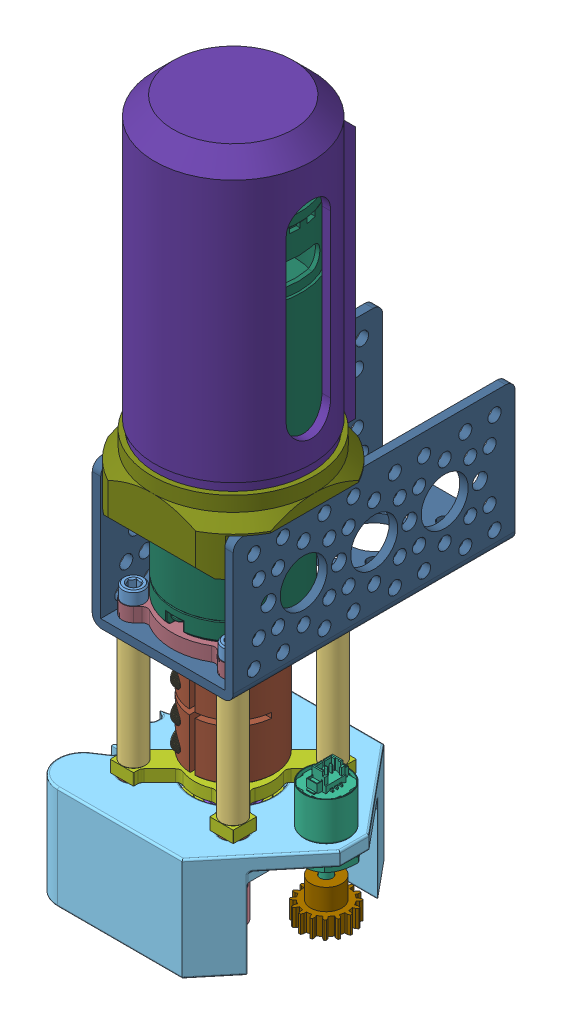
SolidWorks assembly Corner Steering Assembly, configuration Clockwise. Lengths in mm.
Overall size (61.41 192.93 84.4).
42 component instances, 17 part files, 59 mates.
Components (placement in the parent):
- 6-32_SHCS-1: 6-32_SHCS [6-32 SHCS X .250] at (32.5204 -0.254 70.6204) x (-0.999576 0 -0.029101) z (0 1 0)
- 6-32_SHCS-2: 6-32_SHCS [6-32 SHCS X .250] at (5.5796 -0.254 70.6204) x (0.563764 0 -0.825936) z (0 1 0)
- 6-32_SHCS-3: 6-32_SHCS [6-32 SHCS X .250] at (5.5796 -0.254 43.6796) x (-0.984166 0 -0.177249) z (0 1 0)
- 6-32_SHCS-4: 6-32_SHCS [6-32 SHCS X .250] at (32.5204 -0.254 43.6796) x (-0.906181 0 -0.422891) z (0 1 0)
- 6-32_L0_25 Spacer-1: 6-32_L0_25 Spacer [Default] at (5.5796 -34.925 43.6796) x (0 -1 0) z (-0.967859 0 0.251494)
- 6-32_L0_25 Spacer-2: 6-32_L0_25 Spacer [Default] at (32.5204 -34.925 43.6796) x (0 -1 0) z (-0.631957 0 0.775004)
- 6-32_L0_25 Spacer-3: 6-32_L0_25 Spacer [Default] at (5.5796 -34.925 70.6204) x (0 -1 0) z (0 0 1)
- 6-32_L0_25 Spacer-4: 6-32_L0_25 Spacer [Default] at (32.5204 -34.925 70.6204) x (0 -1 0) z (0 0 1)
- 6-32_SHCS-9: 6-32_SHCS [6-32 SHCS X .750] at (32.5204 -25.4 70.6204) x (1 0 0) z (0 -1 0)
- 6-32_SHCS-10: 6-32_SHCS [6-32 SHCS X .750] at (5.5796 -25.4 43.6796) x (1 0 0) z (0 -1 0)
- 6-32_SHCS-11: 6-32_SHCS [6-32 SHCS X .750] at (5.5796 -25.4 70.6204) x (1 0 0) z (0 -1 0)
- 6-32_SHCS-12: 6-32_SHCS [6-32 SHCS X .750] at (32.5204 -25.4 43.6796) x (1 0 0) z (0 -1 0)
- 1_25 threaded standoff-1: 1_25 threaded standoff [Default] at (32.5204 -31.75 43.6796) size (6.34 31.97 6.34)
- 1_25 threaded standoff-2: 1_25 threaded standoff [Default] at (32.5204 -31.75 70.6204) size (6.34 31.97 6.34)
- 1_25 threaded standoff-3: 1_25 threaded standoff [Default] at (5.5796 -31.75 43.6796) size (6.34 31.97 6.34)
- 1_25 threaded standoff-4: 1_25 threaded standoff [Default] at (5.5796 -31.75 70.6204) size (6.34 31.97 6.34)
- .25 D Shaft-1: .25 D Shaft [Default] at (19.05 -24.7728 57.15) x (-0.24409 0 -0.969753) z (-0.969753 0 0.24409)
- Encoder mount-1: Encoder mount [Default] at (19.05 -41.275 57.15)
- Absolute Encoder-1: Absolute Encoder [BEARING VERSION] at (44.196 -41.4528 57.15) x (0 -1 0) z (0 0 -1)
- 0.25 Pillow Bearing Block-1: 0.25 Pillow Bearing Block [Default] at (-9.6584 -13.2725 55.4365) x (0 0 1) z (1 0 0) size (33.27 5.08 33.27)
  - 0.25 Beaing Block-1: 0.25 Beaing Block [Default] at (1.7135 18.4775 28.7084) size (33.27 5.08 33.27)
  - 0.25 Bearing-1: 0.25 Bearing [Default] at (1.7135 21.1636 28.7084) x (0.837169 0 0.546944) z (0.546944 0 -0.837169) size (12.7 4.76 12.7)
- 0.25 Pillow Bearing Block-2: 0.25 Pillow Bearing Block [Default] at (20.7635 -62.9275 85.8584) x (-1 0 0) z (0 0 -1) size (33.27 5.08 33.27)
  - 0.25 Beaing Block-1: 0.25 Beaing Block [Default] at (1.7135 18.4775 28.7084) size (33.27 5.08 33.27)
  - 0.25 Bearing-1: 0.25 Bearing [Default] at (1.7135 21.1636 28.7084) x (0.837169 0 0.546944) z (0.546944 0 -0.837169) size (12.7 4.76 12.7)
- 0.125in Bore 32 Pitch Shaft Mount Pinion Gear-1: 0.125in Bore 32 Pitch Shaft Mount Pinion Gear [Default] at (44.196 -56.7055 57.15) x (-0.355189 0 -0.934794) z (0.934794 0 -0.355189)
- 3 Aluminum Channel-2: 3 Aluminum Channel [Default] at origin
- 0.25 to 6mm Clamping Coupler-1: 0.25 to 6mm Clamping Coupler [Default] at (55.1407 -34.8285 56.8026) x (1 0 0) z (0 1 0) size (50 22.2 75.17)
  - 625100-1: 625100 [Default] at (-36.0907 -0.3474 4.9835) size (22.23 22.2 28.58)
  - 632112_90128A121-1: 632112_90128A121 [Default] at (-1.3244 -7.8756 30.0025) x (0 0 -1) z (1 0 0) size (5.6 5.6 14.62)
  - 632112_90128A121-2: 632112_90128A121 [Default] at (-1.3244 -7.8756 23.5255) x (0 0 -1) z (1 0 0) size (5.6 5.6 14.62)
  - 632112_90128A121-3: 632112_90128A121 [Default] at (-1.3244 -7.8756 15.0165) x (0 0 -1) z (1 0 0) size (5.6 5.6 14.62)
  - 632112_90128A121-4: 632112_90128A121 [Default] at (-1.3244 -7.8756 8.5395) x (0 0 -1) z (1 0 0) size (5.6 5.6 14.62)
- motor mount-1: motor mount [Default] at (-39.8175 39.3823 49.9948) x (-1 0 0) z (0 0 1) size (33.02 8.74 33.02)
  - 555174-1: 555174 [Default] at (-58.8675 33.2863 7.1552) size (33.02 4.05 33.02)
  - 555174 screw_92005A116-1: 555174 screw_92005A116 [Default] at (-68.0596 28.5563 -2.0369) x (1 0 0) z (0 1 0) size (6 6 8.48)
  - 555174 screw_92005A116-2: 555174 screw_92005A116 [Default] at (-68.0596 28.5563 16.3474) x (0 0 -1) z (0 1 0) size (6 6 8.48)
  - 555174 screw_92005A116-3: 555174 screw_92005A116 [Default] at (-49.6753 28.5563 16.3474) x (-1 0 0) z (0 1 0) size (6 6 8.48)
  - 555174 screw_92005A116-4: 555174 screw_92005A116 [Default] at (-49.6753 28.5563 -2.0369) x (0 0 1) z (0 1 0) size (6 6 8.48)
- 638270_Planetary-Motor-1: 638270_Planetary-Motor [Default] at (19.05 6.096 57.15) x (1 0 0) z (0 -1 0) size (37 36.95 124.32)
- motor_mount_base_v2-1: motor_mount_base_v2 [Default] at (19.05 38.1 57.15) x (1 0 0) z (0 1 0) size (44 44 17.61)
- motor_mount_cap_v2-1: motor_mount_cap_v2 [Default] at (19.05 40.7106 57.15) x (1 0 0) z (0 1 0) size (42.38 46.99 83)
Mates (geometry in assembly coordinates):
- Concentric22: concentric anti-aligned: cylinder of Encoder mount-1 through (5.5796 -34.925 43.6796) axis (0 -1 0) radius 3.2258; cylinder of 6-32_L0_25 Spacer-1 through (5.5796 -41.275 43.6796) axis (0 1 0) radius 3.175
- Concentric23: concentric anti-aligned: cylinder of Encoder mount-1 through (32.5204 -34.925 43.6796) axis (0 -1 0) radius 3.2258; cylinder of 6-32_L0_25 Spacer-2 through (32.5204 -41.275 43.6796) axis (0 1 0) radius 3.175
- Concentric24: concentric anti-aligned: cylinder of Encoder mount-1 through (5.5796 -34.925 70.6204) axis (0 -1 0) radius 3.2258; cylinder of 6-32_L0_25 Spacer-3 through (5.5796 -41.275 70.6204) axis (0 1 0) radius 3.175
- Concentric25: concentric anti-aligned: cylinder of Encoder mount-1 through (32.5204 -34.925 70.6204) axis (0 -1 0) radius 3.2258; cylinder of 6-32_L0_25 Spacer-4 through (32.5204 -41.275 70.6204) axis (0 1 0) radius 3.175
- Coincident19: coincident aligned: plane of Encoder mount-1 through (19.05 -41.275 57.15) normal (0 -1 0); plane of 6-32_L0_25 Spacer-3 through (5.5796 -41.275 70.6204) normal (0 -1 0)
- Coincident20: coincident aligned: plane of Encoder mount-1 through (19.05 -41.275 57.15) normal (0 -1 0); plane of 6-32_L0_25 Spacer-1 through (5.5796 -41.275 43.6796) normal (0 -1 0)
- Coincident21: coincident aligned: plane of Encoder mount-1 through (19.05 -41.275 57.15) normal (0 -1 0); plane of 6-32_L0_25 Spacer-2 through (32.5204 -41.275 43.6796) normal (0 -1 0)
- Coincident22: coincident aligned: plane of Encoder mount-1 through (19.05 -41.275 57.15) normal (0 -1 0); plane of 6-32_L0_25 Spacer-4 through (32.5204 -41.275 70.6204) normal (0 -1 0)
- Concentric27: concentric aligned: cylinder of Encoder mount-1 through (44.196 -34.925 57.15) axis (0 -1 0) radius 5.08; cylinder of Absolute Encoder-1 through (44.196 -41.4528 57.15) axis (0 -1 0) radius 6.096
- Coincident24: coincident anti-aligned: plane of Encoder mount-1 through (19.05 -34.925 57.15) normal (0 1 0); plane of Absolute Encoder-1 through (39.7764 -34.925 57.15) normal (0 -1 0)
- Concentric28: concentric anti-aligned: cylinder of 0.25 Pillow Bearing Block-2/0.25 Bearing-1 through (19.05 -44.1452 57.15) axis (0 1 0) radius 3.175; cylinder of 0.25 Pillow Bearing Block-1/0.25 Bearing-1 through (19.05 -32.0548 57.15) axis (0 -1 0) radius 3.175
- Concentric29: concentric aligned: cylinder of 0.25 Pillow Bearing Block-2/0.25 Bearing-1 through (19.05 -44.1452 57.15) axis (0 1 0) radius 3.175; cylinder of .25 D Shaft-1 through (19.05 -88.2728 57.15) axis (0 1 0) radius 3.175
- Coincident30: coincident anti-aligned: plane of 6-32_L0_25 Spacer-4 through (32.5204 -41.275 70.6204) normal (0 -1 0); plane of 0.25 Pillow Bearing Block-2/0.25 Beaing Block-1 through (19.05 -41.275 57.15) normal (0 1 0)
- Concentric30: concentric aligned: cylinder of 0.25 Pillow Bearing Block-1/0.25 Beaing Block-1 through (32.5204 -34.925 43.6796) axis (0 -1 0) radius 1.778; cylinder of 6-32_L0_25 Spacer-2 through (32.5204 -34.925 43.6796) axis (0 -1 0) radius 1.651
- Concentric31: concentric anti-aligned: cylinder of 0.25 Pillow Bearing Block-1/0.25 Beaing Block-1 through (32.5204 -34.925 43.6796) axis (0 -1 0) radius 1.778; cylinder of 0.25 Pillow Bearing Block-2/0.25 Beaing Block-1 through (32.5204 -41.275 43.6796) axis (0 1 0) radius 1.778
- Coincident32: coincident anti-aligned: plane of 6-32_L0_25 Spacer-2 through (32.5204 -34.925 43.6796) normal (0 1 0); plane of 0.25 Pillow Bearing Block-1/0.25 Beaing Block-1 through (19.05 -34.925 57.15) normal (0 -1 0)
- Concentric32: concentric anti-aligned: cylinder of Absolute Encoder-1 through (44.196 -52.2732 57.15) axis (0 1 0) radius 1.5837; cylinder of 0.125in Bore 32 Pitch Shaft Mount Pinion Gear-1 through (44.196 -46.228 57.15) axis (0 -1 0) radius 4.191
- Distance1: distance = 5.08 mm anti-aligned: plane of 0.125in Bore 32 Pitch Shaft Mount Pinion Gear-1 through (44.196 -46.228 57.15) normal (0 1 0); plane of Absolute Encoder-1 through (46.9331 -41.148 69.5516) normal (0 -1 0)
- Coincident36: coincident anti-aligned: plane of 0.25 Pillow Bearing Block-2/0.25 Beaing Block-1 through (19.05 -44.45 57.15) normal (0 -1 0); plane of 6-32_SHCS-9 through (32.5204 -44.45 70.6204) normal (0 1 0)
- Coincident37: coincident anti-aligned: plane of 0.25 Pillow Bearing Block-2/0.25 Beaing Block-1 through (19.05 -44.45 57.15) normal (0 -1 0); plane of 6-32_SHCS-12 through (32.5204 -44.45 43.6796) normal (0 1 0)
- Coincident38: coincident anti-aligned: plane of 0.25 Pillow Bearing Block-2/0.25 Beaing Block-1 through (19.05 -44.45 57.15) normal (0 -1 0); plane of 6-32_SHCS-11 through (5.5796 -44.45 70.6204) normal (0 1 0)
- Coincident39: coincident anti-aligned: plane of 0.25 Pillow Bearing Block-2/0.25 Beaing Block-1 through (19.05 -44.45 57.15) normal (0 -1 0); plane of 6-32_SHCS-10 through (5.5796 -44.45 43.6796) normal (0 1 0)
- Concentric37: concentric anti-aligned: cylinder of Absolute Encoder-1 through (-6.9234 50.0026 121.9749) axis (0 0 -1) radius 1.5837; cylinder of 0.125in Bore 32 Pitch Shaft Mount Pinion Gear-1 through (-6.9234 50.0026 115.9297) axis (0 0 1) radius 4.191
- Concentric40: concentric aligned: cylinder of 6-32_SHCS-2 through (5.5796 18.796 70.6204) axis (0 -1 0) radius 2.8702; cylinder of 3 Aluminum Channel-2 through (5.5796 0 70.6204) axis (0 -1 0) radius 1.778
- Concentric47: concentric aligned: cylinder of 6-32_SHCS-2 through (5.5796 18.796 70.6204) axis (0 -1 0) radius 2.8702; cylinder of 0.25 Pillow Bearing Block-1/0.25 Beaing Block-1 through (5.5796 -34.925 70.6204) axis (0 -1 0) radius 1.778
- Concentric50: concentric aligned: cylinder of 3 Aluminum Channel-2 through (32.5204 0 70.6204) axis (0 -1 0) radius 1.778; cylinder of 6-32_SHCS-1 through (32.5204 18.796 70.6204) axis (0 -1 0) radius 2.8702
- Concentric52: concentric aligned: cylinder of 3 Aluminum Channel-2 through (32.5204 0 43.6796) axis (0 -1 0) radius 1.778; cylinder of 6-32_SHCS-4 through (32.5204 18.796 43.6796) axis (0 -1 0) radius 2.8702
- Concentric53: concentric aligned: cylinder of 3 Aluminum Channel-2 through (32.5204 0 43.6796) axis (0 -1 0) radius 1.778; cylinder of 0.25 Pillow Bearing Block-1/0.25 Beaing Block-1 through (32.5204 -34.925 43.6796) axis (0 -1 0) radius 1.778
- Concentric55: concentric anti-aligned: cylinder of 3 Aluminum Channel-2 through (32.5204 0 43.6796) axis (0 -1 0) radius 1.778; cylinder of 6-32_SHCS-12 through (32.5204 -57.15 43.6796) axis (0 1 0) radius 2.8702
- Coincident55: coordinate: point of 3 Aluminum Channel-2; point of assembly
- Coincident56: coincident anti-aligned: plane of 3 Aluminum Channel-2 through (38.1 0 76.2) normal (0 -1 0); plane of 1_25 threaded standoff-2 through (32.5204 0 70.6204) normal (0 1 0)
- Coincident57: coincident anti-aligned: plane of 3 Aluminum Channel-2 through (38.1 0 76.2) normal (0 -1 0); plane of 1_25 threaded standoff-4 through (5.5796 0 70.6204) normal (0 1 0)
- Coincident58: coincident anti-aligned: plane of 3 Aluminum Channel-2 through (38.1 0 76.2) normal (0 -1 0); plane of 1_25 threaded standoff-3 through (5.5796 0 43.6796) normal (0 1 0)
- Coincident59: coincident anti-aligned: plane of 3 Aluminum Channel-2 through (38.1 0 76.2) normal (0 -1 0); plane of 1_25 threaded standoff-1 through (32.5204 0 43.6796) normal (0 1 0)
- Concentric56: concentric aligned: cylinder of 6-32_SHCS-2 through (5.5796 18.796 70.6204) axis (0 -1 0) radius 2.8702; cylinder of 1_25 threaded standoff-4 through (5.5796 0 70.6204) axis (0 -1 0) radius 3.1712
- Concentric57: concentric aligned: cylinder of 6-32_SHCS-1 through (32.5204 18.796 70.6204) axis (0 -1 0) radius 2.8702; cylinder of 1_25 threaded standoff-2 through (32.5204 0 70.6204) axis (0 -1 0) radius 3.1712
- Concentric58: concentric aligned: cylinder of 6-32_SHCS-3 through (5.5796 18.796 43.6796) axis (0 -1 0) radius 2.8702; cylinder of 1_25 threaded standoff-3 through (5.5796 0 43.6796) axis (0 -1 0) radius 3.1712
- Concentric59: concentric aligned: cylinder of 6-32_SHCS-4 through (32.5204 18.796 43.6796) axis (0 -1 0) radius 2.8702; cylinder of 1_25 threaded standoff-1 through (32.5204 0 43.6796) axis (0 -1 0) radius 3.1712
- Coincident61: coincident anti-aligned: plane of 0.25 Pillow Bearing Block-1/0.25 Beaing Block-1 through (19.05 -31.75 57.15) normal (0 1 0); plane of 1_25 threaded standoff-3 through (5.5796 -31.75 43.6796) normal (0 -1 0)
- Concentric60: concentric aligned: cylinder of 6-32_L0_25 Spacer-4 through (32.5204 -34.925 70.6204) axis (0 -1 0) radius 1.651; cylinder of 1_25 threaded standoff-2 through (32.5204 0 70.6204) axis (0 -1 0) radius 3.1712
- Distance2: distance = 1.27 mm anti-aligned: plane of 0.25 to 6mm Clamping Coupler-1/625100-1 through (19.05 -1.27 57.15) normal (0 1 0); plane of 3 Aluminum Channel-2 through (38.1 0 76.2) normal (0 -1 0)
- Concentric61: concentric aligned: cylinder of .25 D Shaft-1 through (19.05 -88.2728 57.15) axis (0 1 0) radius 3.175; cylinder of 0.25 to 6mm Clamping Coupler-1/625100-1 through (19.05 -15.5575 57.15) axis (0 1 0) radius 3
- Coincident63: coincident anti-aligned: plane of 3 Aluminum Channel-2 through (2.286 2.286 76.2) normal (0 1 0); plane of motor mount-1/555174-1 through (19.05 2.286 57.15) normal (0 -1 0)
- Coincident64: coincident anti-aligned: plane of motor mount-1/555174-1 through (19.05 6.096 57.15) normal (0 1 0); plane of 6-32_SHCS-2 through (5.5796 6.096 70.6204) normal (0 -1 0)
- Coincident66: coincident anti-aligned: plane of motor mount-1/555174-1 through (19.05 6.096 57.15) normal (0 1 0); plane of 6-32_SHCS-1 through (32.5204 6.096 70.6204) normal (0 -1 0)
- Coincident67: coincident anti-aligned: plane of motor mount-1/555174-1 through (19.05 6.096 57.15) normal (0 1 0); plane of 6-32_SHCS-4 through (32.5204 6.096 43.6796) normal (0 -1 0)
- Coincident68: coincident anti-aligned: plane of motor mount-1/555174-1 through (19.05 6.096 57.15) normal (0 1 0); plane of 6-32_SHCS-3 through (5.5796 6.096 43.6796) normal (0 -1 0)
- Concentric62: concentric aligned: cylinder of 3 Aluminum Channel-2 through (19.05 0 57.15) axis (0 -1 0) radius 6.3627; cylinder of motor mount-1/555174-1 through (19.05 6.096 57.15) axis (0 -1 0) radius 10.033
- Concentric63: concentric aligned: cylinder of 1_25 threaded standoff-2 through (32.5204 0 70.6204) axis (0 -1 0) radius 3.1712; cylinder of motor mount-1/555174-1 through (32.5204 16.2585 70.6204) axis (0 -1 0) radius 3.0404
- Concentric64: concentric aligned: cylinder of 1_25 threaded standoff-3 through (5.5796 0 43.6796) axis (0 -1 0) radius 3.1712; cylinder of motor mount-1/555174-1 through (5.5796 16.2585 43.6796) axis (0 -1 0) radius 3.0404
- Concentric65: concentric anti-aligned: cylinder of motor mount-1/555174-1 through (19.05 2.286 57.15) axis (0 1 0) radius 16.51; cylinder of 638270_Planetary-Motor-1 through (19.05 43.456 57.15) axis (0 -1 0) radius 16
- Concentric66: concentric aligned: cylinder of motor mount-1/555174 screw_92005A116-3 through (9.8578 10.826 66.3422) axis (0 -1 0) radius 1.5; cylinder of 638270_Planetary-Motor-1 through (9.8576 6.096 66.3424) axis (0 -1 0) radius 1.25
- Coincident69: coincident anti-aligned: plane of motor mount-1/555174-1 through (19.05 6.096 57.15) normal (0 1 0); plane of 638270_Planetary-Motor-1 through (19.05 6.096 57.15) normal (0 -1 0)
- Parallel2: parallel anti-aligned: plane of 3 Aluminum Channel-2 through (2.286 38.1 76.2) normal (1 0 0); plane of motor_mount_base_v2-1 through (2.4765 27.94 57.15) normal (-1 0 0)
- Concentric72: concentric aligned: cylinder of motor_mount_cap_v2-1 through (19.05 105.7106 57.15) axis (0 -1 0) radius 21.1912; cylinder of 638270_Planetary-Motor-1 through (19.05 43.456 57.15) axis (0 -1 0) radius 16
- Concentric73: concentric aligned: cylinder of motor_mount_cap_v2-1 through (19.05 105.7106 57.15) axis (0 -1 0) radius 21.1912; cylinder of 638270_Planetary-Motor-1 through (19.05 52.806 57.15) axis (0 -1 0) radius 17.82
- Coincident73: coincident anti-aligned: plane of 3 Aluminum Channel-2 through (35.814 38.1 76.2) normal (0 1 0); plane of motor_mount_base_v2-1 through (19.05 38.1 57.15) normal (0 -1 0)
- Concentric74: concentric aligned: cylinder of 638270_Planetary-Motor-1 through (19.05 43.456 57.15) axis (0 -1 0) radius 16; cylinder of motor_mount_base_v2-1 through (19.05 45.55 57.15) axis (0 -1 0) radius 20.691
- Parallel3: parallel anti-aligned: plane of motor_mount_base_v2-1 through (9.65 27.94 35.15) normal (1 0 0); plane of motor_mount_cap_v2-1 through (9.75 105.7106 57.15) normal (-1 0 0)
